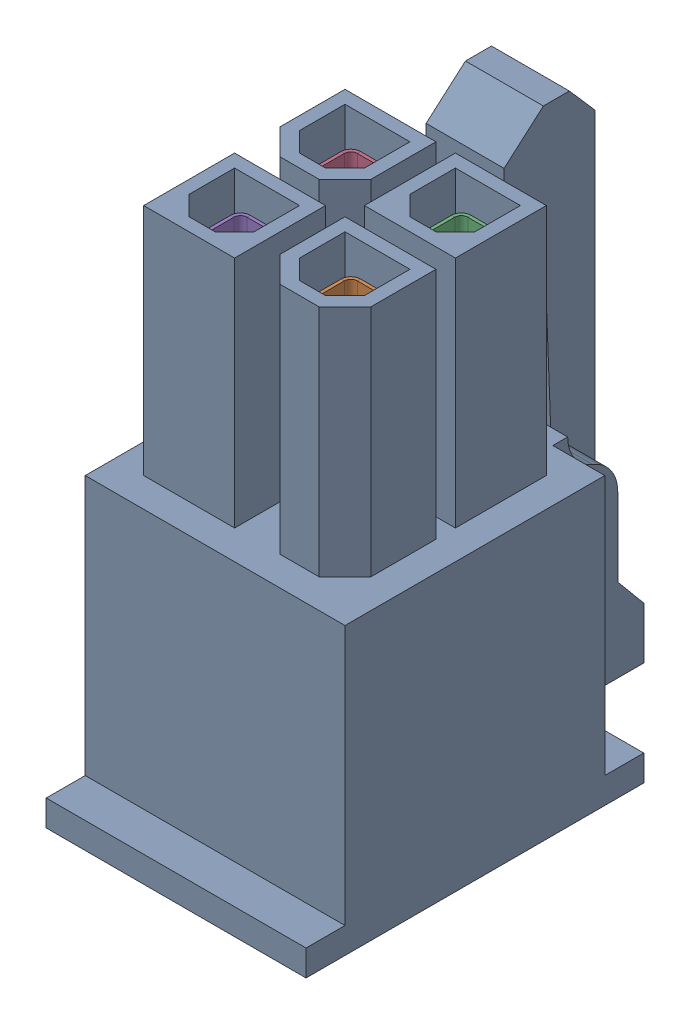
SolidWorks assembly ATX-12V-4-Pin_R3, configuration Default. Lengths in mm.
Overall size (10 21 15).
5 component instances, 2 part files, 0 mates.
Components (placement in the parent):
- ATX-12V-4-Pin-Body_R3-1: ATX-12V-4-Pin-Body_R3 [Default] at (0.2041 -8.9156 21) size (10 21 15)
- ATX-Main-24-Pin-crimp_R3-1: ATX-Main-24-Pin-crimp_R3 [Default] at (2.3291 0.8097 24.15) x (0 1 0) z (-1 0 0) size (15.03 2.9 3.08)
- ATX-Main-24-Pin-crimp_R3-2: ATX-Main-24-Pin-crimp_R3 [Default] at (2.3291 0.8097 19.9) x (0 1 0) z (-1 0 0) size (15.03 2.9 3.08)
- ATX-Main-24-Pin-crimp_R3-3: ATX-Main-24-Pin-crimp_R3 [Default] at (-1.9209 0.8097 19.9) x (0 1 0) z (-1 0 0) size (15.03 2.9 3.08)
- ATX-Main-24-Pin-crimp_R3-4: ATX-Main-24-Pin-crimp_R3 [Default] at (-1.9209 0.8097 24.15) x (0 1 0) z (-1 0 0) size (15.03 2.9 3.08)
